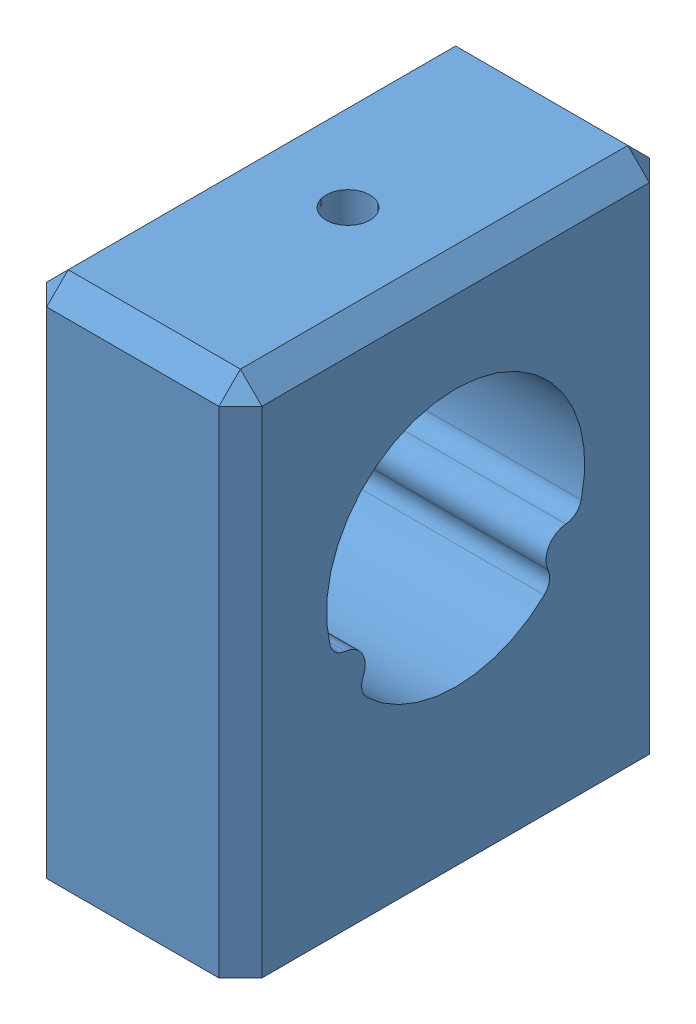
SolidWorks assembly lens_tube_holder, configuration Default. Lengths in mm.
Overall size (25 60 50).
2 component instances, 2 part files, 1 mates.
Components (placement in the parent):
- lens_tube_holder-1: lens_tube_holder [Default] at (1.5123 12.0928 54.7947) size (25 60 50)
- 90291A535_CONFORMABLE SOFT NYLON-TIP SET SCREW-2: 90291A535_CONFORMABLE SOFT NYLON-TIP SET SCREW [90291A535] at (14.0123 44.173 54.8414) x (0.752673 0 -0.658395) z (0 1 0) size (6.52 6.42 11.64)
Mates (geometry in assembly coordinates):
- Concentric1: concentric anti-aligned: circle of lens_tube_holder-1; circle of 90291A535_CONFORMABLE SOFT NYLON-TIP SET SCREW-2
